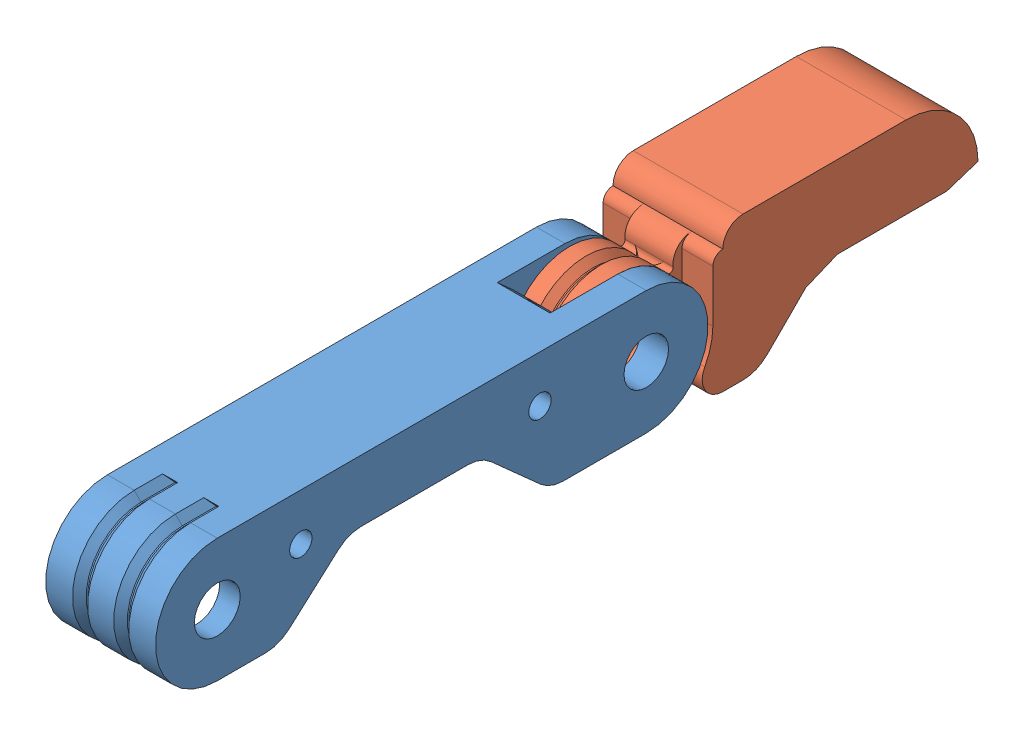
SolidWorks assembly Assem1, configuration Default. Lengths in mm.
Overall size (16.35 23.57 119.47).
2 component instances, 2 part files, 3 mates.
Components (placement in the parent):
- f_d1-1: f_d1 [Default] at (18.2322 52.5338 92.1257) size (16 18 80.5)
- f_d2-1: f_d2 [Default] at (18.5822 52.5338 29.6257) size (16 23.57 57.08)
Mates (geometry in assembly coordinates):
- Concentric1: concentric: cylinder of f_d1-1 through (26.2322 52.5338 29.6257) axis (-1 0 0) radius 3.25; cylinder of ? through (26.5822 52.5338 29.6257) axis (-1 0 0) radius 3.35
- Coincident6: coincident: plane of f_d1-1 through (22.0822 52.5338 29.6257) normal (-1 0 0); plane of ? through (22.0822 52.5338 29.6257) normal (1 0 0)
- Parallel2: parallel: plane of assembly; plane of assembly; plane of f_d1-1 through (26.2322 61.5338 92.1257) normal (0 1 0); plane of f_d2-1 through (-32.0943 64.4838 15.8812) normal (0 1 0)
